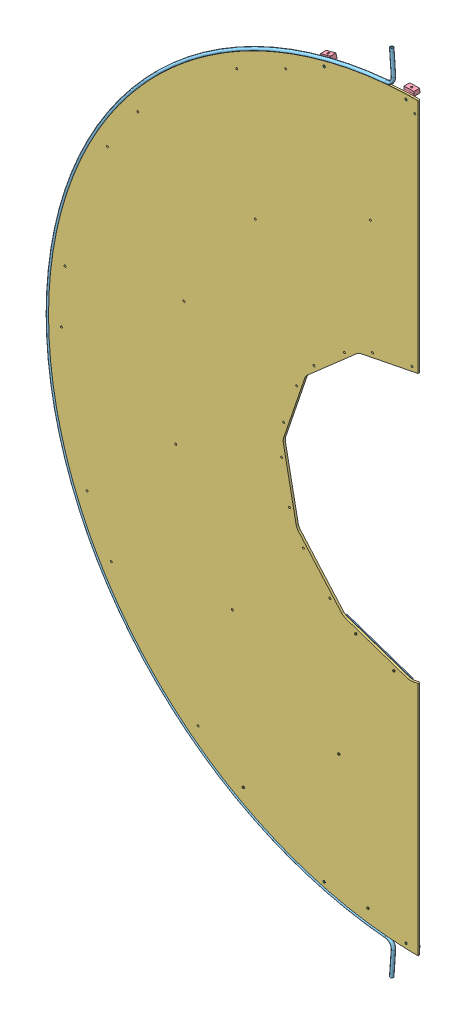
SolidWorks assembly FVTX read_ckt_brd2_array, configuration No array. Lengths in mm.
Overall size (623.69 1199.01 14.3).
281 component instances, 8 part files, 20 mates.
Components (placement in the parent):
- FVTX rear_ckt_board_assy3-1: FVTX rear_ckt_board_assy3 [outline drawing] x (0.94693 -0.321439 0) z (0 0 -1) size (276.95 346.3 2.31)
  - FVTX rear_ckt_board_assy3-1: FVTX rear_ckt_board_assy3 [outline drawing] at origin size (276.95 346.3 1.59)
  - hirose df18c series receptacle-4: hirose df18c series receptacle [DF18C-60DS-0.4V] at (-42.4321 213.3208 1.5875) x (0.19509 -0.980785 0) z (0 0 1) size (5 14.6 0.73)
  - hirose df18c series receptacle-68: hirose df18c series receptacle [DF18C-60DS-0.4V] at (-44.383 223.1287 1.5875) x (0.19509 -0.980785 0) z (0 0 1) size (5 14.6 0.73)
  - hirose df18c series receptacle-12: hirose df18c series receptacle [DF18C-100DS-0.4V] at (-47.3094 237.8404 1.5875) x (0.19509 -0.980785 0) z (0 0 1) size (5 22.6 0.73)
  - hirose df18c series receptacle-41: hirose df18c series receptacle [DF18C-100DS-0.4V] at (-52.1867 262.3601 1.5875) x (0.19509 -0.980785 0) z (0 0 1) size (5 22.6 0.73)
  - hirose df18c series receptacle-45: hirose df18c series receptacle [DF18C-100DS-0.4V] at (-57.0639 286.8797 1.5875) x (0.19509 -0.980785 0) z (0 0 1) size (5 22.6 0.73)
  - hirose df18c series receptacle-65: hirose df18c series receptacle [DF18C-60DS-0.4V] at (-14.2252 217.0343 1.5875) x (0.065403 -0.997859 0) z (0 0 1) size (5 14.6 0.73)
  - hirose df18c series receptacle-66: hirose df18c series receptacle [DF18C-60DS-0.4V] at (14.2252 217.0343 1.5875) x (-0.065403 -0.997859 0) z (0 0 1) size (5 14.6 0.73)
  - hirose df18c series receptacle-67: hirose df18c series receptacle [DF18C-60DS-0.4V] at (42.4321 213.3208 1.5875) x (-0.19509 -0.980785 0) z (0 0 1) size (5 14.6 0.73)
  - hirose df18c series receptacle-38: hirose df18c series receptacle [DF18C-100DS-0.4V] at (-15.8603 241.9808 1.5875) x (0.065403 -0.997859 0) z (0 0 1) size (5 22.6 0.73)
  - hirose df18c series receptacle-39: hirose df18c series receptacle [DF18C-100DS-0.4V] at (15.8603 241.9808 1.5875) x (-0.065403 -0.997859 0) z (0 0 1) size (5 22.6 0.73)
  - hirose df18c series receptacle-40: hirose df18c series receptacle [DF18C-100DS-0.4V] at (47.3094 237.8404 1.5875) x (-0.19509 -0.980785 0) z (0 0 1) size (5 22.6 0.73)
  - hirose df18c series receptacle-42: hirose df18c series receptacle [DF18C-100DS-0.4V] at (-17.4953 266.9273 1.5875) x (0.065403 -0.997859 0) z (0 0 1) size (5 22.6 0.73)
  - hirose df18c series receptacle-43: hirose df18c series receptacle [DF18C-100DS-0.4V] at (17.4953 266.9273 1.5875) x (-0.065403 -0.997859 0) z (0 0 1) size (5 22.6 0.73)
  - hirose df18c series receptacle-44: hirose df18c series receptacle [DF18C-100DS-0.4V] at (52.1867 262.3601 1.5875) x (-0.19509 -0.980785 0) z (0 0 1) size (5 22.6 0.73)
  - hirose df18c series receptacle-46: hirose df18c series receptacle [DF18C-100DS-0.4V] at (-19.1304 291.8737 1.5875) x (0.065403 -0.997859 0) z (0 0 1) size (5 22.6 0.73)
  - hirose df18c series receptacle-47: hirose df18c series receptacle [DF18C-100DS-0.4V] at (19.1304 291.8737 1.5875) x (-0.065403 -0.997859 0) z (0 0 1) size (5 22.6 0.73)
  - hirose df18c series receptacle-48: hirose df18c series receptacle [DF18C-100DS-0.4V] at (57.0639 286.8797 1.5875) x (-0.19509 -0.980785 0) z (0 0 1) size (5 22.6 0.73)
  - VTX - pan cross head_ai-1: VTX - pan cross head_ai [CR-PHMS 0.112-40x0.25x0.25-N] at (-98.0409 523.0976 3.6195) x (0 0 -1) z (1 0 0) (suppressed, hidden)
  - VTX - pan cross head_ai-2: VTX - pan cross head_ai [CR-PHMS 0.112-40x0.25x0.25-N] at (98.0409 523.0976 3.6195) x (0 0 -1) z (1 0 0) (suppressed, hidden)
  - VTX - pan cross head_ai-3: VTX - pan cross head_ai [CR-PHMS 0.112-40x0.25x0.25-N] at (0 369.15 3.6195) x (0 0 -1) z (1 0 0) (suppressed, hidden)
  - VTX - pan cross head_ai-4: VTX - pan cross head_ai [CR-PHMS 0.112-40x0.25x0.25-N] at (-30 202.35 3.6195) x (0 0 -1) z (1 0 0) (suppressed, hidden)
  - VTX - pan cross head_ai-5: VTX - pan cross head_ai [CR-PHMS 0.112-40x0.25x0.25-N] at (30 202.35 3.6195) x (0 0 -1) z (1 0 0) (suppressed, hidden)
  - hirose df18c series receptacle-69: hirose df18c series receptacle [DF18C-100DS-0.4V] at (-49.2603 247.6483 1.5875) x (0.19509 -0.980785 0) z (0 0 1) size (5 22.6 0.73)
  - hirose df18c series receptacle-70: hirose df18c series receptacle [DF18C-100DS-0.4V] at (-54.1376 272.1679 1.5875) x (0.19509 -0.980785 0) z (0 0 1) size (5 22.6 0.73)
  - hirose df18c series receptacle-71: hirose df18c series receptacle [DF18C-100DS-0.4V] at (-59.0148 296.6875 1.5875) x (0.19509 -0.980785 0) z (0 0 1) size (5 22.6 0.73)
  - hirose df18c series receptacle-72: hirose df18c series receptacle [DF18C-60DS-0.4V] at (-14.8792 227.0129 1.5875) x (0.065403 -0.997859 0) z (0 0 1) size (5 14.6 0.73)
  - hirose df18c series receptacle-73: hirose df18c series receptacle [DF18C-60DS-0.4V] at (14.8792 227.0129 1.5875) x (-0.065403 -0.997859 0) z (0 0 1) size (5 14.6 0.73)
  - hirose df18c series receptacle-74: hirose df18c series receptacle [DF18C-60DS-0.4V] at (44.383 223.1287 1.5875) x (-0.19509 -0.980785 0) z (0 0 1) size (5 14.6 0.73)
  - hirose df18c series receptacle-75: hirose df18c series receptacle [DF18C-100DS-0.4V] at (-16.5143 251.9594 1.5875) x (0.065403 -0.997859 0) z (0 0 1) size (5 22.6 0.73)
  - hirose df18c series receptacle-76: hirose df18c series receptacle [DF18C-100DS-0.4V] at (16.5143 251.9594 1.5875) x (-0.065403 -0.997859 0) z (0 0 1) size (5 22.6 0.73)
  - hirose df18c series receptacle-77: hirose df18c series receptacle [DF18C-100DS-0.4V] at (49.2603 247.6483 1.5875) x (-0.19509 -0.980785 0) z (0 0 1) size (5 22.6 0.73)
  - hirose df18c series receptacle-78: hirose df18c series receptacle [DF18C-100DS-0.4V] at (-18.1494 276.9059 1.5875) x (0.065403 -0.997859 0) z (0 0 1) size (5 22.6 0.73)
  - hirose df18c series receptacle-79: hirose df18c series receptacle [DF18C-100DS-0.4V] at (18.1494 276.9059 1.5875) x (-0.065403 -0.997859 0) z (0 0 1) size (5 22.6 0.73)
  - hirose df18c series receptacle-80: hirose df18c series receptacle [DF18C-100DS-0.4V] at (54.1376 272.1679 1.5875) x (-0.19509 -0.980785 0) z (0 0 1) size (5 22.6 0.73)
  - hirose df18c series receptacle-81: hirose df18c series receptacle [DF18C-100DS-0.4V] at (-19.7844 301.8523 1.5875) x (0.065403 -0.997859 0) z (0 0 1) size (5 22.6 0.73)
  - hirose df18c series receptacle-82: hirose df18c series receptacle [DF18C-100DS-0.4V] at (19.7844 301.8523 1.5875) x (-0.065403 -0.997859 0) z (0 0 1) size (5 22.6 0.73)
  - hirose df18c series receptacle-83: hirose df18c series receptacle [DF18C-100DS-0.4V] at (59.0148 296.6875 1.5875) x (-0.19509 -0.980785 0) z (0 0 1) size (5 22.6 0.73)
- Bigwheel plate assy-1: Bigwheel plate assy [FVTX Cooling Plate] at (0 0 2.0875) x (1 0 0) z (0 0 -1) size (554.56 1199.01 14)
  - Bigwheel plate-1: Bigwheel plate [FVTX Cooling Plate] at origin size (550.41 1103.14 3.17)
  - Bigwheel plate mounting block-1: Bigwheel plate mounting block [Default] at (-19.3971 -555.4614 1.5875) x (0 0 -1) z (-0.999391 0.034899 0) size (10.03 15 15)
  - Bigwheel plate mounting block-2: Bigwheel plate mounting block [Default] at (-19.3971 555.4614 1.5875) x (0 0 -1) z (0.999391 0.034899 0) size (10.03 15 15)
  - Bigwheel plate mounting block-3: Bigwheel plate mounting block [Default] at (-143.8516 536.8616 1.5875) x (0 0 -1) z (0.965926 0.258819 0) size (10.03 15 15)
  - Bigwheel plate mounting block-4: Bigwheel plate mounting block [Default] at (-143.8516 -536.8616 1.5875) x (0 0 -1) z (-0.965926 0.258819 0) size (10.03 15 15)
  - Bigwheel plate mounting block-6: Bigwheel plate mounting block [Default] at (-17.6242 -504.6924 -1.5875) x (0 0 1) z (0.999391 -0.034899 0) size (10.03 15 15) (suppressed, hidden)
  - Bigwheel plate mounting block-8: Bigwheel plate mounting block [Default] at (-17.6242 504.6924 -1.5875) x (0 0 1) z (-0.999391 -0.034899 0) size (10.03 15 15) (suppressed, hidden)
  - Bigwheel plate mounting block-10: Bigwheel plate mounting block [Default] at (-130.7036 487.7925 -1.5875) x (0 0 1) z (-0.965926 -0.258819 0) size (10.03 15 15) (suppressed, hidden)
  - Bigwheel plate mounting block-12: Bigwheel plate mounting block [Default] at (-130.7036 -487.7925 -1.5875) x (0 0 1) z (0.965926 -0.258819 0) size (10.03 15 15) (suppressed, hidden)
  - Bigwheel plate cooling tube-1: Bigwheel plate cooling tube [FVTX Bigwheel] x (0 1 0) z (0 0 1) size (1199.01 518.62 4.76)
  - Bigwheels seal-1: Bigwheels seal [Default] at (0 0 -20.437) (suppressed, hidden)
  - VTX - Flat Head Screw_AM-1: VTX - Flat Head Screw_AM [B18.6.7M - M3 x 0.5 x 5 Type I Cross Recessed FHMS --5N] at (-18.9969 543.9997 3.225) x (0 0 -1) z (-0.92007 -0.391753 0) size (5 5.5 5.5)
  - VTX - Flat Head Screw_AM-2: VTX - Flat Head Screw_AM [B18.6.7M - M3 x 0.5 x 5 Type I Cross Recessed FHMS --5N] at (-140.8833 525.7836 3.225) x (0 0 -1) z (-0.029274 -0.999571 0) size (5 5.5 5.5)
  - VTX - Flat Head Screw_AM-3: VTX - Flat Head Screw_AM [B18.6.7M - M3 x 0.5 x 5 Type I Cross Recessed FHMS --5N] at (-18.9969 -543.9997 3.225) x (0 0 -1) z (-0.924921 -0.38016 0) size (5 5.5 5.5)
  - VTX - Flat Head Screw_AM-4: VTX - Flat Head Screw_AM [B18.6.7M - M3 x 0.5 x 5 Type I Cross Recessed FHMS --5N] at (-140.8833 -525.7836 3.225) x (0 0 -1) z (0.994263 0.106964 0) size (5 5.5 5.5)
- Bigwheels seal-1: Bigwheels seal [FVTX seal] at (0 0 -21.2044) (suppressed, hidden)
- VTX - pan cross head_ai-1: VTX - pan cross head_ai [CR-PHMS 0.112-40x0.25x0.25-N] at (-118.6594 -349.5593 -3.6195) x (0 0 1) z (-1 0 0)
- VTX - pan cross head_ai-2: VTX - pan cross head_ai [CR-PHMS 0.112-40x0.25x0.25-N] at (-75.3063 -526.8511 -3.6195) x (0 0 1) z (-1 0 0)
- VTX - pan cross head_ai-4: VTX - pan cross head_ai [CR-PHMS 0.112-40x0.25x0.25-N] at (-260.9821 -463.8226 -3.6195) x (0 0 1) z (-1 0 0)
- VTX - pan cross head_ai-5: VTX - pan cross head_ai [CR-PHMS 0.112-40x0.25x0.25-N] at (-93.4512 -181.9681 -3.6195) x (0 0 1) z (-1 0 0)
- VTX - pan cross head_ai-6: VTX - pan cross head_ai [CR-PHMS 0.112-40x0.25x0.25-N] at (-36.6354 -201.2545 -3.6195) x (0 0 1) z (-1 0 0)
- VTX - pan cross head_ai-7: VTX - pan cross head_ai [CR-PHMS 0.112-40x0.25x0.25-N] at (-132.3544 -155.9738 -3.6195) x (0 0 1) z (-0.866025 0.5 0) (suppressed, hidden)
- VTX - pan cross head_ai-8: VTX - pan cross head_ai [CR-PHMS 0.112-40x0.25x0.25-N] at (-192.6092 -68.9001 -3.6195) x (0 0 1) z (-0.5 0.866025 0) (suppressed, hidden)
- VTX - pan cross head_ai-9: VTX - pan cross head_ai [CR-PHMS 0.112-40x0.25x0.25-N] at (-201.2545 36.6354 -3.6195) x (0 0 1) z (0 1 0) (suppressed, hidden)
- VTX - pan cross head_ai-10: VTX - pan cross head_ai [CR-PHMS 0.112-40x0.25x0.25-N] at (-155.9738 132.3544 -3.6195) x (0 0 1) z (0.5 0.866025 0) (suppressed, hidden)
- VTX - pan cross head_ai-11: VTX - pan cross head_ai [CR-PHMS 0.112-40x0.25x0.25-N] at (-68.9001 192.6092 -3.6195) x (0 0 1) z (0.866025 0.5 0) (suppressed, hidden)
- VTX - pan cross head_ai-12: VTX - pan cross head_ai [CR-PHMS 0.112-40x0.25x0.25-N] at (-171.9152 -110.8634 -3.6195) x (0 0 1) z (-0.866025 0.5 0) (suppressed, hidden)
- VTX - pan cross head_ai-13: VTX - pan cross head_ai [CR-PHMS 0.112-40x0.25x0.25-N] at (-204.3146 -10.053 -3.6195) x (0 0 1) z (-0.5 0.866025 0) (suppressed, hidden)
- VTX - pan cross head_ai-14: VTX - pan cross head_ai [CR-PHMS 0.112-40x0.25x0.25-N] at (-181.9681 93.4512 -3.6195) x (0 0 1) z (0 1 0) (suppressed, hidden)
- VTX - pan cross head_ai-15: VTX - pan cross head_ai [CR-PHMS 0.112-40x0.25x0.25-N] at (-110.8634 171.9152 -3.6195) x (0 0 1) z (0.5 0.866025 0) (suppressed, hidden)
- VTX - pan cross head_ai-16: VTX - pan cross head_ai [CR-PHMS 0.112-40x0.25x0.25-N] at (-10.053 204.3146 -3.6195) x (0 0 1) z (0.866025 0.5 0) (suppressed, hidden)
- VTX - pan cross head_ai-17: VTX - pan cross head_ai [CR-PHMS 0.112-40x0.25x0.25-N] at (-457.9285 -271.1911 -3.6195) x (0 0 1) z (-0.866025 0.5 0) (suppressed, hidden)
- VTX - pan cross head_ai-18: VTX - pan cross head_ai [CR-PHMS 0.112-40x0.25x0.25-N] at (-532.1732 -5.8942 -3.6195) x (0 0 1) z (-0.5 0.866025 0) (suppressed, hidden)
- VTX - pan cross head_ai-19: VTX - pan cross head_ai [CR-PHMS 0.112-40x0.25x0.25-N] at (-463.8226 260.9821 -3.6195) x (0 0 1) z (0 1 0) (suppressed, hidden)
- VTX - pan cross head_ai-20: VTX - pan cross head_ai [CR-PHMS 0.112-40x0.25x0.25-N] at (-271.1911 457.9285 -3.6195) x (0 0 1) z (0.5 0.866025 0) (suppressed, hidden)
- VTX - pan cross head_ai-21: VTX - pan cross head_ai [CR-PHMS 0.112-40x0.25x0.25-N] at (-5.8942 532.1732 -3.6195) x (0 0 1) z (0.866025 0.5 0) (suppressed, hidden)
- VTX - pan cross head_ai-22: VTX - pan cross head_ai [CR-PHMS 0.112-40x0.25x0.25-N] at (-328.6427 -418.6133 -3.6195) x (0 0 1) z (-0.866025 0.5 0) (suppressed, hidden)
- VTX - pan cross head_ai-23: VTX - pan cross head_ai [CR-PHMS 0.112-40x0.25x0.25-N] at (-493.9196 -198.2084 -3.6195) x (0 0 1) z (-0.5 0.866025 0) (suppressed, hidden)
- VTX - pan cross head_ai-24: VTX - pan cross head_ai [CR-PHMS 0.112-40x0.25x0.25-N] at (-526.8511 75.3063 -3.6195) x (0 0 1) z (0 1 0) (suppressed, hidden)
- VTX - pan cross head_ai-25: VTX - pan cross head_ai [CR-PHMS 0.112-40x0.25x0.25-N] at (-418.6133 328.6427 -3.6195) x (0 0 1) z (0.5 0.866025 0) (suppressed, hidden)
- VTX - pan cross head_ai-26: VTX - pan cross head_ai [CR-PHMS 0.112-40x0.25x0.25-N] at (-198.2084 493.9196 -3.6195) x (0 0 1) z (0.866025 0.5 0) (suppressed, hidden)
- VTX - pan cross head_ai-27: VTX - pan cross head_ai [CR-PHMS 0.112-40x0.25x0.25-N] at (-277.5417 -243.3975 -3.6195) x (0 0 1) z (-0.866025 0.5 0) (suppressed, hidden)
- VTX - pan cross head_ai-28: VTX - pan cross head_ai [CR-PHMS 0.112-40x0.25x0.25-N] at (-362.0569 -72.0176 -3.6195) x (0 0 1) z (-0.5 0.866025 0) (suppressed, hidden)
- VTX - pan cross head_ai-29: VTX - pan cross head_ai [CR-PHMS 0.112-40x0.25x0.25-N] at (-349.5593 118.6594 -3.6195) x (0 0 1) z (0 1 0) (suppressed, hidden)
- VTX - pan cross head_ai-30: VTX - pan cross head_ai [CR-PHMS 0.112-40x0.25x0.25-N] at (-243.3975 277.5417 -3.6195) x (0 0 1) z (0.5 0.866025 0) (suppressed, hidden)
- VTX - pan cross head_ai-31: VTX - pan cross head_ai [CR-PHMS 0.112-40x0.25x0.25-N] at (-72.0176 362.0569 -3.6195) x (0 0 1) z (0.866025 0.5 0) (suppressed, hidden)
- FVTX rear_ckt_board_assy3-16: FVTX rear_ckt_board_assy3 [outline drawing] x (0.659346 -0.75184 0) z (0 0 -1) size (276.95 346.3 2.31) (suppressed, hidden)
  - FVTX rear_ckt_board_assy3-1: FVTX rear_ckt_board_assy3 [outline drawing] at origin size (276.95 346.3 1.59)
  - hirose df18c series receptacle-4: hirose df18c series receptacle [DF18C-60DS-0.4V] at (-42.4321 213.3208 1.5875) x (0.19509 -0.980785 0) z (0 0 1) size (5 14.6 0.73)
  - hirose df18c series receptacle-68: hirose df18c series receptacle [DF18C-60DS-0.4V] at (-44.383 223.1287 1.5875) x (0.19509 -0.980785 0) z (0 0 1) size (5 14.6 0.73)
  - hirose df18c series receptacle-12: hirose df18c series receptacle [DF18C-100DS-0.4V] at (-47.3094 237.8404 1.5875) x (0.19509 -0.980785 0) z (0 0 1) size (5 22.6 0.73)
  - hirose df18c series receptacle-41: hirose df18c series receptacle [DF18C-100DS-0.4V] at (-52.1867 262.3601 1.5875) x (0.19509 -0.980785 0) z (0 0 1) size (5 22.6 0.73)
  - hirose df18c series receptacle-45: hirose df18c series receptacle [DF18C-100DS-0.4V] at (-57.0639 286.8797 1.5875) x (0.19509 -0.980785 0) z (0 0 1) size (5 22.6 0.73)
  - hirose df18c series receptacle-65: hirose df18c series receptacle [DF18C-60DS-0.4V] at (-14.2252 217.0343 1.5875) x (0.065403 -0.997859 0) z (0 0 1) size (5 14.6 0.73)
  - hirose df18c series receptacle-66: hirose df18c series receptacle [DF18C-60DS-0.4V] at (14.2252 217.0343 1.5875) x (-0.065403 -0.997859 0) z (0 0 1) size (5 14.6 0.73)
  - hirose df18c series receptacle-67: hirose df18c series receptacle [DF18C-60DS-0.4V] at (42.4321 213.3208 1.5875) x (-0.19509 -0.980785 0) z (0 0 1) size (5 14.6 0.73)
  - hirose df18c series receptacle-38: hirose df18c series receptacle [DF18C-100DS-0.4V] at (-15.8603 241.9808 1.5875) x (0.065403 -0.997859 0) z (0 0 1) size (5 22.6 0.73)
  - hirose df18c series receptacle-39: hirose df18c series receptacle [DF18C-100DS-0.4V] at (15.8603 241.9808 1.5875) x (-0.065403 -0.997859 0) z (0 0 1) size (5 22.6 0.73)
  - hirose df18c series receptacle-40: hirose df18c series receptacle [DF18C-100DS-0.4V] at (47.3094 237.8404 1.5875) x (-0.19509 -0.980785 0) z (0 0 1) size (5 22.6 0.73)
  - hirose df18c series receptacle-42: hirose df18c series receptacle [DF18C-100DS-0.4V] at (-17.4953 266.9273 1.5875) x (0.065403 -0.997859 0) z (0 0 1) size (5 22.6 0.73)
  - hirose df18c series receptacle-43: hirose df18c series receptacle [DF18C-100DS-0.4V] at (17.4953 266.9273 1.5875) x (-0.065403 -0.997859 0) z (0 0 1) size (5 22.6 0.73)
  - hirose df18c series receptacle-44: hirose df18c series receptacle [DF18C-100DS-0.4V] at (52.1867 262.3601 1.5875) x (-0.19509 -0.980785 0) z (0 0 1) size (5 22.6 0.73)
  - hirose df18c series receptacle-46: hirose df18c series receptacle [DF18C-100DS-0.4V] at (-19.1304 291.8737 1.5875) x (0.065403 -0.997859 0) z (0 0 1) size (5 22.6 0.73)
  - hirose df18c series receptacle-47: hirose df18c series receptacle [DF18C-100DS-0.4V] at (19.1304 291.8737 1.5875) x (-0.065403 -0.997859 0) z (0 0 1) size (5 22.6 0.73)
  - hirose df18c series receptacle-48: hirose df18c series receptacle [DF18C-100DS-0.4V] at (57.0639 286.8797 1.5875) x (-0.19509 -0.980785 0) z (0 0 1) size (5 22.6 0.73)
  - VTX - pan cross head_ai-1: VTX - pan cross head_ai [CR-PHMS 0.112-40x0.25x0.25-N] at (-98.0409 523.0976 3.6195) x (0 0 -1) z (1 0 0) (suppressed, hidden)
  - VTX - pan cross head_ai-2: VTX - pan cross head_ai [CR-PHMS 0.112-40x0.25x0.25-N] at (98.0409 523.0976 3.6195) x (0 0 -1) z (1 0 0) (suppressed, hidden)
  - VTX - pan cross head_ai-3: VTX - pan cross head_ai [CR-PHMS 0.112-40x0.25x0.25-N] at (0 369.15 3.6195) x (0 0 -1) z (1 0 0) (suppressed, hidden)
  - VTX - pan cross head_ai-4: VTX - pan cross head_ai [CR-PHMS 0.112-40x0.25x0.25-N] at (-30 202.35 3.6195) x (0 0 -1) z (1 0 0) (suppressed, hidden)
  - VTX - pan cross head_ai-5: VTX - pan cross head_ai [CR-PHMS 0.112-40x0.25x0.25-N] at (30 202.35 3.6195) x (0 0 -1) z (1 0 0) (suppressed, hidden)
  - hirose df18c series receptacle-69: hirose df18c series receptacle [DF18C-100DS-0.4V] at (-49.2603 247.6483 1.5875) x (0.19509 -0.980785 0) z (0 0 1) size (5 22.6 0.73)
  - hirose df18c series receptacle-70: hirose df18c series receptacle [DF18C-100DS-0.4V] at (-54.1376 272.1679 1.5875) x (0.19509 -0.980785 0) z (0 0 1) size (5 22.6 0.73)
  - hirose df18c series receptacle-71: hirose df18c series receptacle [DF18C-100DS-0.4V] at (-59.0148 296.6875 1.5875) x (0.19509 -0.980785 0) z (0 0 1) size (5 22.6 0.73)
  - hirose df18c series receptacle-72: hirose df18c series receptacle [DF18C-60DS-0.4V] at (-14.8792 227.0129 1.5875) x (0.065403 -0.997859 0) z (0 0 1) size (5 14.6 0.73)
  - hirose df18c series receptacle-73: hirose df18c series receptacle [DF18C-60DS-0.4V] at (14.8792 227.0129 1.5875) x (-0.065403 -0.997859 0) z (0 0 1) size (5 14.6 0.73)
  - hirose df18c series receptacle-74: hirose df18c series receptacle [DF18C-60DS-0.4V] at (44.383 223.1287 1.5875) x (-0.19509 -0.980785 0) z (0 0 1) size (5 14.6 0.73)
  - hirose df18c series receptacle-75: hirose df18c series receptacle [DF18C-100DS-0.4V] at (-16.5143 251.9594 1.5875) x (0.065403 -0.997859 0) z (0 0 1) size (5 22.6 0.73)
  - hirose df18c series receptacle-76: hirose df18c series receptacle [DF18C-100DS-0.4V] at (16.5143 251.9594 1.5875) x (-0.065403 -0.997859 0) z (0 0 1) size (5 22.6 0.73)
  - hirose df18c series receptacle-77: hirose df18c series receptacle [DF18C-100DS-0.4V] at (49.2603 247.6483 1.5875) x (-0.19509 -0.980785 0) z (0 0 1) size (5 22.6 0.73)
  - hirose df18c series receptacle-78: hirose df18c series receptacle [DF18C-100DS-0.4V] at (-18.1494 276.9059 1.5875) x (0.065403 -0.997859 0) z (0 0 1) size (5 22.6 0.73)
  - hirose df18c series receptacle-79: hirose df18c series receptacle [DF18C-100DS-0.4V] at (18.1494 276.9059 1.5875) x (-0.065403 -0.997859 0) z (0 0 1) size (5 22.6 0.73)
  - hirose df18c series receptacle-80: hirose df18c series receptacle [DF18C-100DS-0.4V] at (54.1376 272.1679 1.5875) x (-0.19509 -0.980785 0) z (0 0 1) size (5 22.6 0.73)
  - hirose df18c series receptacle-81: hirose df18c series receptacle [DF18C-100DS-0.4V] at (-19.7844 301.8523 1.5875) x (0.065403 -0.997859 0) z (0 0 1) size (5 22.6 0.73)
  - hirose df18c series receptacle-82: hirose df18c series receptacle [DF18C-100DS-0.4V] at (19.7844 301.8523 1.5875) x (-0.065403 -0.997859 0) z (0 0 1) size (5 22.6 0.73)
  - hirose df18c series receptacle-83: hirose df18c series receptacle [DF18C-100DS-0.4V] at (59.0148 296.6875 1.5875) x (-0.19509 -0.980785 0) z (0 0 1) size (5 22.6 0.73)
- FVTX rear_ckt_board_assy3-17: FVTX rear_ckt_board_assy3 [outline drawing] x (0.19509 -0.980785 0) z (0 0 -1) size (276.95 346.3 2.31) (suppressed, hidden)
  - FVTX rear_ckt_board_assy3-1: FVTX rear_ckt_board_assy3 [outline drawing] at origin size (276.95 346.3 1.59)
  - hirose df18c series receptacle-4: hirose df18c series receptacle [DF18C-60DS-0.4V] at (-42.4321 213.3208 1.5875) x (0.19509 -0.980785 0) z (0 0 1) size (5 14.6 0.73)
  - hirose df18c series receptacle-68: hirose df18c series receptacle [DF18C-60DS-0.4V] at (-44.383 223.1287 1.5875) x (0.19509 -0.980785 0) z (0 0 1) size (5 14.6 0.73)
  - hirose df18c series receptacle-12: hirose df18c series receptacle [DF18C-100DS-0.4V] at (-47.3094 237.8404 1.5875) x (0.19509 -0.980785 0) z (0 0 1) size (5 22.6 0.73)
  - hirose df18c series receptacle-41: hirose df18c series receptacle [DF18C-100DS-0.4V] at (-52.1867 262.3601 1.5875) x (0.19509 -0.980785 0) z (0 0 1) size (5 22.6 0.73)
  - hirose df18c series receptacle-45: hirose df18c series receptacle [DF18C-100DS-0.4V] at (-57.0639 286.8797 1.5875) x (0.19509 -0.980785 0) z (0 0 1) size (5 22.6 0.73)
  - hirose df18c series receptacle-65: hirose df18c series receptacle [DF18C-60DS-0.4V] at (-14.2252 217.0343 1.5875) x (0.065403 -0.997859 0) z (0 0 1) size (5 14.6 0.73)
  - hirose df18c series receptacle-66: hirose df18c series receptacle [DF18C-60DS-0.4V] at (14.2252 217.0343 1.5875) x (-0.065403 -0.997859 0) z (0 0 1) size (5 14.6 0.73)
  - hirose df18c series receptacle-67: hirose df18c series receptacle [DF18C-60DS-0.4V] at (42.4321 213.3208 1.5875) x (-0.19509 -0.980785 0) z (0 0 1) size (5 14.6 0.73)
  - hirose df18c series receptacle-38: hirose df18c series receptacle [DF18C-100DS-0.4V] at (-15.8603 241.9808 1.5875) x (0.065403 -0.997859 0) z (0 0 1) size (5 22.6 0.73)
  - hirose df18c series receptacle-39: hirose df18c series receptacle [DF18C-100DS-0.4V] at (15.8603 241.9808 1.5875) x (-0.065403 -0.997859 0) z (0 0 1) size (5 22.6 0.73)
  - hirose df18c series receptacle-40: hirose df18c series receptacle [DF18C-100DS-0.4V] at (47.3094 237.8404 1.5875) x (-0.19509 -0.980785 0) z (0 0 1) size (5 22.6 0.73)
  - hirose df18c series receptacle-42: hirose df18c series receptacle [DF18C-100DS-0.4V] at (-17.4953 266.9273 1.5875) x (0.065403 -0.997859 0) z (0 0 1) size (5 22.6 0.73)
  - hirose df18c series receptacle-43: hirose df18c series receptacle [DF18C-100DS-0.4V] at (17.4953 266.9273 1.5875) x (-0.065403 -0.997859 0) z (0 0 1) size (5 22.6 0.73)
  - hirose df18c series receptacle-44: hirose df18c series receptacle [DF18C-100DS-0.4V] at (52.1867 262.3601 1.5875) x (-0.19509 -0.980785 0) z (0 0 1) size (5 22.6 0.73)
  - hirose df18c series receptacle-46: hirose df18c series receptacle [DF18C-100DS-0.4V] at (-19.1304 291.8737 1.5875) x (0.065403 -0.997859 0) z (0 0 1) size (5 22.6 0.73)
  - hirose df18c series receptacle-47: hirose df18c series receptacle [DF18C-100DS-0.4V] at (19.1304 291.8737 1.5875) x (-0.065403 -0.997859 0) z (0 0 1) size (5 22.6 0.73)
  - hirose df18c series receptacle-48: hirose df18c series receptacle [DF18C-100DS-0.4V] at (57.0639 286.8797 1.5875) x (-0.19509 -0.980785 0) z (0 0 1) size (5 22.6 0.73)
  - VTX - pan cross head_ai-1: VTX - pan cross head_ai [CR-PHMS 0.112-40x0.25x0.25-N] at (-98.0409 523.0976 3.6195) x (0 0 -1) z (1 0 0) (suppressed, hidden)
  - VTX - pan cross head_ai-2: VTX - pan cross head_ai [CR-PHMS 0.112-40x0.25x0.25-N] at (98.0409 523.0976 3.6195) x (0 0 -1) z (1 0 0) (suppressed, hidden)
  - VTX - pan cross head_ai-3: VTX - pan cross head_ai [CR-PHMS 0.112-40x0.25x0.25-N] at (0 369.15 3.6195) x (0 0 -1) z (1 0 0) (suppressed, hidden)
  - VTX - pan cross head_ai-4: VTX - pan cross head_ai [CR-PHMS 0.112-40x0.25x0.25-N] at (-30 202.35 3.6195) x (0 0 -1) z (1 0 0) (suppressed, hidden)
  - VTX - pan cross head_ai-5: VTX - pan cross head_ai [CR-PHMS 0.112-40x0.25x0.25-N] at (30 202.35 3.6195) x (0 0 -1) z (1 0 0) (suppressed, hidden)
  - hirose df18c series receptacle-69: hirose df18c series receptacle [DF18C-100DS-0.4V] at (-49.2603 247.6483 1.5875) x (0.19509 -0.980785 0) z (0 0 1) size (5 22.6 0.73)
  - hirose df18c series receptacle-70: hirose df18c series receptacle [DF18C-100DS-0.4V] at (-54.1376 272.1679 1.5875) x (0.19509 -0.980785 0) z (0 0 1) size (5 22.6 0.73)
  - hirose df18c series receptacle-71: hirose df18c series receptacle [DF18C-100DS-0.4V] at (-59.0148 296.6875 1.5875) x (0.19509 -0.980785 0) z (0 0 1) size (5 22.6 0.73)
  - hirose df18c series receptacle-72: hirose df18c series receptacle [DF18C-60DS-0.4V] at (-14.8792 227.0129 1.5875) x (0.065403 -0.997859 0) z (0 0 1) size (5 14.6 0.73)
  - hirose df18c series receptacle-73: hirose df18c series receptacle [DF18C-60DS-0.4V] at (14.8792 227.0129 1.5875) x (-0.065403 -0.997859 0) z (0 0 1) size (5 14.6 0.73)
  - hirose df18c series receptacle-74: hirose df18c series receptacle [DF18C-60DS-0.4V] at (44.383 223.1287 1.5875) x (-0.19509 -0.980785 0) z (0 0 1) size (5 14.6 0.73)
  - hirose df18c series receptacle-75: hirose df18c series receptacle [DF18C-100DS-0.4V] at (-16.5143 251.9594 1.5875) x (0.065403 -0.997859 0) z (0 0 1) size (5 22.6 0.73)
  - hirose df18c series receptacle-76: hirose df18c series receptacle [DF18C-100DS-0.4V] at (16.5143 251.9594 1.5875) x (-0.065403 -0.997859 0) z (0 0 1) size (5 22.6 0.73)
  - hirose df18c series receptacle-77: hirose df18c series receptacle [DF18C-100DS-0.4V] at (49.2603 247.6483 1.5875) x (-0.19509 -0.980785 0) z (0 0 1) size (5 22.6 0.73)
  - hirose df18c series receptacle-78: hirose df18c series receptacle [DF18C-100DS-0.4V] at (-18.1494 276.9059 1.5875) x (0.065403 -0.997859 0) z (0 0 1) size (5 22.6 0.73)
  - hirose df18c series receptacle-79: hirose df18c series receptacle [DF18C-100DS-0.4V] at (18.1494 276.9059 1.5875) x (-0.065403 -0.997859 0) z (0 0 1) size (5 22.6 0.73)
  - hirose df18c series receptacle-80: hirose df18c series receptacle [DF18C-100DS-0.4V] at (54.1376 272.1679 1.5875) x (-0.19509 -0.980785 0) z (0 0 1) size (5 22.6 0.73)
  - hirose df18c series receptacle-81: hirose df18c series receptacle [DF18C-100DS-0.4V] at (-19.7844 301.8523 1.5875) x (0.065403 -0.997859 0) z (0 0 1) size (5 22.6 0.73)
  - hirose df18c series receptacle-82: hirose df18c series receptacle [DF18C-100DS-0.4V] at (19.7844 301.8523 1.5875) x (-0.065403 -0.997859 0) z (0 0 1) size (5 22.6 0.73)
  - hirose df18c series receptacle-83: hirose df18c series receptacle [DF18C-100DS-0.4V] at (59.0148 296.6875 1.5875) x (-0.19509 -0.980785 0) z (0 0 1) size (5 22.6 0.73)
- FVTX rear_ckt_board_assy3-18: FVTX rear_ckt_board_assy3 [outline drawing] x (-0.321439 -0.94693 0) z (0 0 -1) size (276.95 346.3 2.31) (suppressed, hidden)
  - FVTX rear_ckt_board_assy3-1: FVTX rear_ckt_board_assy3 [outline drawing] at origin size (276.95 346.3 1.59)
  - hirose df18c series receptacle-4: hirose df18c series receptacle [DF18C-60DS-0.4V] at (-42.4321 213.3208 1.5875) x (0.19509 -0.980785 0) z (0 0 1) size (5 14.6 0.73)
  - hirose df18c series receptacle-68: hirose df18c series receptacle [DF18C-60DS-0.4V] at (-44.383 223.1287 1.5875) x (0.19509 -0.980785 0) z (0 0 1) size (5 14.6 0.73)
  - hirose df18c series receptacle-12: hirose df18c series receptacle [DF18C-100DS-0.4V] at (-47.3094 237.8404 1.5875) x (0.19509 -0.980785 0) z (0 0 1) size (5 22.6 0.73)
  - hirose df18c series receptacle-41: hirose df18c series receptacle [DF18C-100DS-0.4V] at (-52.1867 262.3601 1.5875) x (0.19509 -0.980785 0) z (0 0 1) size (5 22.6 0.73)
  - hirose df18c series receptacle-45: hirose df18c series receptacle [DF18C-100DS-0.4V] at (-57.0639 286.8797 1.5875) x (0.19509 -0.980785 0) z (0 0 1) size (5 22.6 0.73)
  - hirose df18c series receptacle-65: hirose df18c series receptacle [DF18C-60DS-0.4V] at (-14.2252 217.0343 1.5875) x (0.065403 -0.997859 0) z (0 0 1) size (5 14.6 0.73)
  - hirose df18c series receptacle-66: hirose df18c series receptacle [DF18C-60DS-0.4V] at (14.2252 217.0343 1.5875) x (-0.065403 -0.997859 0) z (0 0 1) size (5 14.6 0.73)
  - hirose df18c series receptacle-67: hirose df18c series receptacle [DF18C-60DS-0.4V] at (42.4321 213.3208 1.5875) x (-0.19509 -0.980785 0) z (0 0 1) size (5 14.6 0.73)
  - hirose df18c series receptacle-38: hirose df18c series receptacle [DF18C-100DS-0.4V] at (-15.8603 241.9808 1.5875) x (0.065403 -0.997859 0) z (0 0 1) size (5 22.6 0.73)
  - hirose df18c series receptacle-39: hirose df18c series receptacle [DF18C-100DS-0.4V] at (15.8603 241.9808 1.5875) x (-0.065403 -0.997859 0) z (0 0 1) size (5 22.6 0.73)
  - hirose df18c series receptacle-40: hirose df18c series receptacle [DF18C-100DS-0.4V] at (47.3094 237.8404 1.5875) x (-0.19509 -0.980785 0) z (0 0 1) size (5 22.6 0.73)
  - hirose df18c series receptacle-42: hirose df18c series receptacle [DF18C-100DS-0.4V] at (-17.4953 266.9273 1.5875) x (0.065403 -0.997859 0) z (0 0 1) size (5 22.6 0.73)
  - hirose df18c series receptacle-43: hirose df18c series receptacle [DF18C-100DS-0.4V] at (17.4953 266.9273 1.5875) x (-0.065403 -0.997859 0) z (0 0 1) size (5 22.6 0.73)
  - hirose df18c series receptacle-44: hirose df18c series receptacle [DF18C-100DS-0.4V] at (52.1867 262.3601 1.5875) x (-0.19509 -0.980785 0) z (0 0 1) size (5 22.6 0.73)
  - hirose df18c series receptacle-46: hirose df18c series receptacle [DF18C-100DS-0.4V] at (-19.1304 291.8737 1.5875) x (0.065403 -0.997859 0) z (0 0 1) size (5 22.6 0.73)
  - hirose df18c series receptacle-47: hirose df18c series receptacle [DF18C-100DS-0.4V] at (19.1304 291.8737 1.5875) x (-0.065403 -0.997859 0) z (0 0 1) size (5 22.6 0.73)
  - hirose df18c series receptacle-48: hirose df18c series receptacle [DF18C-100DS-0.4V] at (57.0639 286.8797 1.5875) x (-0.19509 -0.980785 0) z (0 0 1) size (5 22.6 0.73)
  - VTX - pan cross head_ai-1: VTX - pan cross head_ai [CR-PHMS 0.112-40x0.25x0.25-N] at (-98.0409 523.0976 3.6195) x (0 0 -1) z (1 0 0) (suppressed, hidden)
  - VTX - pan cross head_ai-2: VTX - pan cross head_ai [CR-PHMS 0.112-40x0.25x0.25-N] at (98.0409 523.0976 3.6195) x (0 0 -1) z (1 0 0) (suppressed, hidden)
  - VTX - pan cross head_ai-3: VTX - pan cross head_ai [CR-PHMS 0.112-40x0.25x0.25-N] at (0 369.15 3.6195) x (0 0 -1) z (1 0 0) (suppressed, hidden)
  - VTX - pan cross head_ai-4: VTX - pan cross head_ai [CR-PHMS 0.112-40x0.25x0.25-N] at (-30 202.35 3.6195) x (0 0 -1) z (1 0 0) (suppressed, hidden)
  - VTX - pan cross head_ai-5: VTX - pan cross head_ai [CR-PHMS 0.112-40x0.25x0.25-N] at (30 202.35 3.6195) x (0 0 -1) z (1 0 0) (suppressed, hidden)
  - hirose df18c series receptacle-69: hirose df18c series receptacle [DF18C-100DS-0.4V] at (-49.2603 247.6483 1.5875) x (0.19509 -0.980785 0) z (0 0 1) size (5 22.6 0.73)
  - hirose df18c series receptacle-70: hirose df18c series receptacle [DF18C-100DS-0.4V] at (-54.1376 272.1679 1.5875) x (0.19509 -0.980785 0) z (0 0 1) size (5 22.6 0.73)
  - hirose df18c series receptacle-71: hirose df18c series receptacle [DF18C-100DS-0.4V] at (-59.0148 296.6875 1.5875) x (0.19509 -0.980785 0) z (0 0 1) size (5 22.6 0.73)
  - hirose df18c series receptacle-72: hirose df18c series receptacle [DF18C-60DS-0.4V] at (-14.8792 227.0129 1.5875) x (0.065403 -0.997859 0) z (0 0 1) size (5 14.6 0.73)
  - hirose df18c series receptacle-73: hirose df18c series receptacle [DF18C-60DS-0.4V] at (14.8792 227.0129 1.5875) x (-0.065403 -0.997859 0) z (0 0 1) size (5 14.6 0.73)
  - hirose df18c series receptacle-74: hirose df18c series receptacle [DF18C-60DS-0.4V] at (44.383 223.1287 1.5875) x (-0.19509 -0.980785 0) z (0 0 1) size (5 14.6 0.73)
  - hirose df18c series receptacle-75: hirose df18c series receptacle [DF18C-100DS-0.4V] at (-16.5143 251.9594 1.5875) x (0.065403 -0.997859 0) z (0 0 1) size (5 22.6 0.73)
  - hirose df18c series receptacle-76: hirose df18c series receptacle [DF18C-100DS-0.4V] at (16.5143 251.9594 1.5875) x (-0.065403 -0.997859 0) z (0 0 1) size (5 22.6 0.73)
  - hirose df18c series receptacle-77: hirose df18c series receptacle [DF18C-100DS-0.4V] at (49.2603 247.6483 1.5875) x (-0.19509 -0.980785 0) z (0 0 1) size (5 22.6 0.73)
  - hirose df18c series receptacle-78: hirose df18c series receptacle [DF18C-100DS-0.4V] at (-18.1494 276.9059 1.5875) x (0.065403 -0.997859 0) z (0 0 1) size (5 22.6 0.73)
  - hirose df18c series receptacle-79: hirose df18c series receptacle [DF18C-100DS-0.4V] at (18.1494 276.9059 1.5875) x (-0.065403 -0.997859 0) z (0 0 1) size (5 22.6 0.73)
  - hirose df18c series receptacle-80: hirose df18c series receptacle [DF18C-100DS-0.4V] at (54.1376 272.1679 1.5875) x (-0.19509 -0.980785 0) z (0 0 1) size (5 22.6 0.73)
  - hirose df18c series receptacle-81: hirose df18c series receptacle [DF18C-100DS-0.4V] at (-19.7844 301.8523 1.5875) x (0.065403 -0.997859 0) z (0 0 1) size (5 22.6 0.73)
  - hirose df18c series receptacle-82: hirose df18c series receptacle [DF18C-100DS-0.4V] at (19.7844 301.8523 1.5875) x (-0.065403 -0.997859 0) z (0 0 1) size (5 22.6 0.73)
  - hirose df18c series receptacle-83: hirose df18c series receptacle [DF18C-100DS-0.4V] at (59.0148 296.6875 1.5875) x (-0.19509 -0.980785 0) z (0 0 1) size (5 22.6 0.73)
- FVTX rear_ckt_board_assy3-19: FVTX rear_ckt_board_assy3 [outline drawing] x (-0.75184 -0.659346 0) z (0 0 -1) size (276.95 346.3 2.31) (suppressed, hidden)
  - FVTX rear_ckt_board_assy3-1: FVTX rear_ckt_board_assy3 [outline drawing] at origin size (276.95 346.3 1.59)
  - hirose df18c series receptacle-4: hirose df18c series receptacle [DF18C-60DS-0.4V] at (-42.4321 213.3208 1.5875) x (0.19509 -0.980785 0) z (0 0 1) size (5 14.6 0.73)
  - hirose df18c series receptacle-68: hirose df18c series receptacle [DF18C-60DS-0.4V] at (-44.383 223.1287 1.5875) x (0.19509 -0.980785 0) z (0 0 1) size (5 14.6 0.73)
  - hirose df18c series receptacle-12: hirose df18c series receptacle [DF18C-100DS-0.4V] at (-47.3094 237.8404 1.5875) x (0.19509 -0.980785 0) z (0 0 1) size (5 22.6 0.73)
  - hirose df18c series receptacle-41: hirose df18c series receptacle [DF18C-100DS-0.4V] at (-52.1867 262.3601 1.5875) x (0.19509 -0.980785 0) z (0 0 1) size (5 22.6 0.73)
  - hirose df18c series receptacle-45: hirose df18c series receptacle [DF18C-100DS-0.4V] at (-57.0639 286.8797 1.5875) x (0.19509 -0.980785 0) z (0 0 1) size (5 22.6 0.73)
  - hirose df18c series receptacle-65: hirose df18c series receptacle [DF18C-60DS-0.4V] at (-14.2252 217.0343 1.5875) x (0.065403 -0.997859 0) z (0 0 1) size (5 14.6 0.73)
  - hirose df18c series receptacle-66: hirose df18c series receptacle [DF18C-60DS-0.4V] at (14.2252 217.0343 1.5875) x (-0.065403 -0.997859 0) z (0 0 1) size (5 14.6 0.73)
  - hirose df18c series receptacle-67: hirose df18c series receptacle [DF18C-60DS-0.4V] at (42.4321 213.3208 1.5875) x (-0.19509 -0.980785 0) z (0 0 1) size (5 14.6 0.73)
  - hirose df18c series receptacle-38: hirose df18c series receptacle [DF18C-100DS-0.4V] at (-15.8603 241.9808 1.5875) x (0.065403 -0.997859 0) z (0 0 1) size (5 22.6 0.73)
  - hirose df18c series receptacle-39: hirose df18c series receptacle [DF18C-100DS-0.4V] at (15.8603 241.9808 1.5875) x (-0.065403 -0.997859 0) z (0 0 1) size (5 22.6 0.73)
  - hirose df18c series receptacle-40: hirose df18c series receptacle [DF18C-100DS-0.4V] at (47.3094 237.8404 1.5875) x (-0.19509 -0.980785 0) z (0 0 1) size (5 22.6 0.73)
  - hirose df18c series receptacle-42: hirose df18c series receptacle [DF18C-100DS-0.4V] at (-17.4953 266.9273 1.5875) x (0.065403 -0.997859 0) z (0 0 1) size (5 22.6 0.73)
  - hirose df18c series receptacle-43: hirose df18c series receptacle [DF18C-100DS-0.4V] at (17.4953 266.9273 1.5875) x (-0.065403 -0.997859 0) z (0 0 1) size (5 22.6 0.73)
  - hirose df18c series receptacle-44: hirose df18c series receptacle [DF18C-100DS-0.4V] at (52.1867 262.3601 1.5875) x (-0.19509 -0.980785 0) z (0 0 1) size (5 22.6 0.73)
  - hirose df18c series receptacle-46: hirose df18c series receptacle [DF18C-100DS-0.4V] at (-19.1304 291.8737 1.5875) x (0.065403 -0.997859 0) z (0 0 1) size (5 22.6 0.73)
  - hirose df18c series receptacle-47: hirose df18c series receptacle [DF18C-100DS-0.4V] at (19.1304 291.8737 1.5875) x (-0.065403 -0.997859 0) z (0 0 1) size (5 22.6 0.73)
  - hirose df18c series receptacle-48: hirose df18c series receptacle [DF18C-100DS-0.4V] at (57.0639 286.8797 1.5875) x (-0.19509 -0.980785 0) z (0 0 1) size (5 22.6 0.73)
  - VTX - pan cross head_ai-1: VTX - pan cross head_ai [CR-PHMS 0.112-40x0.25x0.25-N] at (-98.0409 523.0976 3.6195) x (0 0 -1) z (1 0 0) (suppressed, hidden)
  - VTX - pan cross head_ai-2: VTX - pan cross head_ai [CR-PHMS 0.112-40x0.25x0.25-N] at (98.0409 523.0976 3.6195) x (0 0 -1) z (1 0 0) (suppressed, hidden)
  - VTX - pan cross head_ai-3: VTX - pan cross head_ai [CR-PHMS 0.112-40x0.25x0.25-N] at (0 369.15 3.6195) x (0 0 -1) z (1 0 0) (suppressed, hidden)
  - VTX - pan cross head_ai-4: VTX - pan cross head_ai [CR-PHMS 0.112-40x0.25x0.25-N] at (-30 202.35 3.6195) x (0 0 -1) z (1 0 0) (suppressed, hidden)
  - VTX - pan cross head_ai-5: VTX - pan cross head_ai [CR-PHMS 0.112-40x0.25x0.25-N] at (30 202.35 3.6195) x (0 0 -1) z (1 0 0) (suppressed, hidden)
  - hirose df18c series receptacle-69: hirose df18c series receptacle [DF18C-100DS-0.4V] at (-49.2603 247.6483 1.5875) x (0.19509 -0.980785 0) z (0 0 1) size (5 22.6 0.73)
  - hirose df18c series receptacle-70: hirose df18c series receptacle [DF18C-100DS-0.4V] at (-54.1376 272.1679 1.5875) x (0.19509 -0.980785 0) z (0 0 1) size (5 22.6 0.73)
  - hirose df18c series receptacle-71: hirose df18c series receptacle [DF18C-100DS-0.4V] at (-59.0148 296.6875 1.5875) x (0.19509 -0.980785 0) z (0 0 1) size (5 22.6 0.73)
  - hirose df18c series receptacle-72: hirose df18c series receptacle [DF18C-60DS-0.4V] at (-14.8792 227.0129 1.5875) x (0.065403 -0.997859 0) z (0 0 1) size (5 14.6 0.73)
  - hirose df18c series receptacle-73: hirose df18c series receptacle [DF18C-60DS-0.4V] at (14.8792 227.0129 1.5875) x (-0.065403 -0.997859 0) z (0 0 1) size (5 14.6 0.73)
  - hirose df18c series receptacle-74: hirose df18c series receptacle [DF18C-60DS-0.4V] at (44.383 223.1287 1.5875) x (-0.19509 -0.980785 0) z (0 0 1) size (5 14.6 0.73)
  - hirose df18c series receptacle-75: hirose df18c series receptacle [DF18C-100DS-0.4V] at (-16.5143 251.9594 1.5875) x (0.065403 -0.997859 0) z (0 0 1) size (5 22.6 0.73)
  - hirose df18c series receptacle-76: hirose df18c series receptacle [DF18C-100DS-0.4V] at (16.5143 251.9594 1.5875) x (-0.065403 -0.997859 0) z (0 0 1) size (5 22.6 0.73)
  - hirose df18c series receptacle-77: hirose df18c series receptacle [DF18C-100DS-0.4V] at (49.2603 247.6483 1.5875) x (-0.19509 -0.980785 0) z (0 0 1) size (5 22.6 0.73)
  - hirose df18c series receptacle-78: hirose df18c series receptacle [DF18C-100DS-0.4V] at (-18.1494 276.9059 1.5875) x (0.065403 -0.997859 0) z (0 0 1) size (5 22.6 0.73)
  - hirose df18c series receptacle-79: hirose df18c series receptacle [DF18C-100DS-0.4V] at (18.1494 276.9059 1.5875) x (-0.065403 -0.997859 0) z (0 0 1) size (5 22.6 0.73)
  - hirose df18c series receptacle-80: hirose df18c series receptacle [DF18C-100DS-0.4V] at (54.1376 272.1679 1.5875) x (-0.19509 -0.980785 0) z (0 0 1) size (5 22.6 0.73)
  - hirose df18c series receptacle-81: hirose df18c series receptacle [DF18C-100DS-0.4V] at (-19.7844 301.8523 1.5875) x (0.065403 -0.997859 0) z (0 0 1) size (5 22.6 0.73)
  - hirose df18c series receptacle-82: hirose df18c series receptacle [DF18C-100DS-0.4V] at (19.7844 301.8523 1.5875) x (-0.065403 -0.997859 0) z (0 0 1) size (5 22.6 0.73)
  - hirose df18c series receptacle-83: hirose df18c series receptacle [DF18C-100DS-0.4V] at (59.0148 296.6875 1.5875) x (-0.19509 -0.980785 0) z (0 0 1) size (5 22.6 0.73)
- FVTX rear_ckt_board_assy3-20: FVTX rear_ckt_board_assy3 [outline drawing] x (-0.980785 -0.19509 0) z (0 0 -1) size (276.95 346.3 2.31) (suppressed, hidden)
  - FVTX rear_ckt_board_assy3-1: FVTX rear_ckt_board_assy3 [outline drawing] at origin size (276.95 346.3 1.59)
  - hirose df18c series receptacle-4: hirose df18c series receptacle [DF18C-60DS-0.4V] at (-42.4321 213.3208 1.5875) x (0.19509 -0.980785 0) z (0 0 1) size (5 14.6 0.73)
  - hirose df18c series receptacle-68: hirose df18c series receptacle [DF18C-60DS-0.4V] at (-44.383 223.1287 1.5875) x (0.19509 -0.980785 0) z (0 0 1) size (5 14.6 0.73)
  - hirose df18c series receptacle-12: hirose df18c series receptacle [DF18C-100DS-0.4V] at (-47.3094 237.8404 1.5875) x (0.19509 -0.980785 0) z (0 0 1) size (5 22.6 0.73)
  - hirose df18c series receptacle-41: hirose df18c series receptacle [DF18C-100DS-0.4V] at (-52.1867 262.3601 1.5875) x (0.19509 -0.980785 0) z (0 0 1) size (5 22.6 0.73)
  - hirose df18c series receptacle-45: hirose df18c series receptacle [DF18C-100DS-0.4V] at (-57.0639 286.8797 1.5875) x (0.19509 -0.980785 0) z (0 0 1) size (5 22.6 0.73)
  - hirose df18c series receptacle-65: hirose df18c series receptacle [DF18C-60DS-0.4V] at (-14.2252 217.0343 1.5875) x (0.065403 -0.997859 0) z (0 0 1) size (5 14.6 0.73)
  - hirose df18c series receptacle-66: hirose df18c series receptacle [DF18C-60DS-0.4V] at (14.2252 217.0343 1.5875) x (-0.065403 -0.997859 0) z (0 0 1) size (5 14.6 0.73)
  - hirose df18c series receptacle-67: hirose df18c series receptacle [DF18C-60DS-0.4V] at (42.4321 213.3208 1.5875) x (-0.19509 -0.980785 0) z (0 0 1) size (5 14.6 0.73)
  - hirose df18c series receptacle-38: hirose df18c series receptacle [DF18C-100DS-0.4V] at (-15.8603 241.9808 1.5875) x (0.065403 -0.997859 0) z (0 0 1) size (5 22.6 0.73)
  - hirose df18c series receptacle-39: hirose df18c series receptacle [DF18C-100DS-0.4V] at (15.8603 241.9808 1.5875) x (-0.065403 -0.997859 0) z (0 0 1) size (5 22.6 0.73)
  - hirose df18c series receptacle-40: hirose df18c series receptacle [DF18C-100DS-0.4V] at (47.3094 237.8404 1.5875) x (-0.19509 -0.980785 0) z (0 0 1) size (5 22.6 0.73)
  - hirose df18c series receptacle-42: hirose df18c series receptacle [DF18C-100DS-0.4V] at (-17.4953 266.9273 1.5875) x (0.065403 -0.997859 0) z (0 0 1) size (5 22.6 0.73)
  - hirose df18c series receptacle-43: hirose df18c series receptacle [DF18C-100DS-0.4V] at (17.4953 266.9273 1.5875) x (-0.065403 -0.997859 0) z (0 0 1) size (5 22.6 0.73)
  - hirose df18c series receptacle-44: hirose df18c series receptacle [DF18C-100DS-0.4V] at (52.1867 262.3601 1.5875) x (-0.19509 -0.980785 0) z (0 0 1) size (5 22.6 0.73)
  - hirose df18c series receptacle-46: hirose df18c series receptacle [DF18C-100DS-0.4V] at (-19.1304 291.8737 1.5875) x (0.065403 -0.997859 0) z (0 0 1) size (5 22.6 0.73)
  - hirose df18c series receptacle-47: hirose df18c series receptacle [DF18C-100DS-0.4V] at (19.1304 291.8737 1.5875) x (-0.065403 -0.997859 0) z (0 0 1) size (5 22.6 0.73)
  - hirose df18c series receptacle-48: hirose df18c series receptacle [DF18C-100DS-0.4V] at (57.0639 286.8797 1.5875) x (-0.19509 -0.980785 0) z (0 0 1) size (5 22.6 0.73)
  - VTX - pan cross head_ai-1: VTX - pan cross head_ai [CR-PHMS 0.112-40x0.25x0.25-N] at (-98.0409 523.0976 3.6195) x (0 0 -1) z (1 0 0) (suppressed, hidden)
  - VTX - pan cross head_ai-2: VTX - pan cross head_ai [CR-PHMS 0.112-40x0.25x0.25-N] at (98.0409 523.0976 3.6195) x (0 0 -1) z (1 0 0) (suppressed, hidden)
  - VTX - pan cross head_ai-3: VTX - pan cross head_ai [CR-PHMS 0.112-40x0.25x0.25-N] at (0 369.15 3.6195) x (0 0 -1) z (1 0 0) (suppressed, hidden)
  - VTX - pan cross head_ai-4: VTX - pan cross head_ai [CR-PHMS 0.112-40x0.25x0.25-N] at (-30 202.35 3.6195) x (0 0 -1) z (1 0 0) (suppressed, hidden)
  - VTX - pan cross head_ai-5: VTX - pan cross head_ai [CR-PHMS 0.112-40x0.25x0.25-N] at (30 202.35 3.6195) x (0 0 -1) z (1 0 0) (suppressed, hidden)
  - hirose df18c series receptacle-69: hirose df18c series receptacle [DF18C-100DS-0.4V] at (-49.2603 247.6483 1.5875) x (0.19509 -0.980785 0) z (0 0 1) size (5 22.6 0.73)
  - hirose df18c series receptacle-70: hirose df18c series receptacle [DF18C-100DS-0.4V] at (-54.1376 272.1679 1.5875) x (0.19509 -0.980785 0) z (0 0 1) size (5 22.6 0.73)
  - hirose df18c series receptacle-71: hirose df18c series receptacle [DF18C-100DS-0.4V] at (-59.0148 296.6875 1.5875) x (0.19509 -0.980785 0) z (0 0 1) size (5 22.6 0.73)
  - hirose df18c series receptacle-72: hirose df18c series receptacle [DF18C-60DS-0.4V] at (-14.8792 227.0129 1.5875) x (0.065403 -0.997859 0) z (0 0 1) size (5 14.6 0.73)
  - hirose df18c series receptacle-73: hirose df18c series receptacle [DF18C-60DS-0.4V] at (14.8792 227.0129 1.5875) x (-0.065403 -0.997859 0) z (0 0 1) size (5 14.6 0.73)
  - hirose df18c series receptacle-74: hirose df18c series receptacle [DF18C-60DS-0.4V] at (44.383 223.1287 1.5875) x (-0.19509 -0.980785 0) z (0 0 1) size (5 14.6 0.73)
  - hirose df18c series receptacle-75: hirose df18c series receptacle [DF18C-100DS-0.4V] at (-16.5143 251.9594 1.5875) x (0.065403 -0.997859 0) z (0 0 1) size (5 22.6 0.73)
  - hirose df18c series receptacle-76: hirose df18c series receptacle [DF18C-100DS-0.4V] at (16.5143 251.9594 1.5875) x (-0.065403 -0.997859 0) z (0 0 1) size (5 22.6 0.73)
  - hirose df18c series receptacle-77: hirose df18c series receptacle [DF18C-100DS-0.4V] at (49.2603 247.6483 1.5875) x (-0.19509 -0.980785 0) z (0 0 1) size (5 22.6 0.73)
  - hirose df18c series receptacle-78: hirose df18c series receptacle [DF18C-100DS-0.4V] at (-18.1494 276.9059 1.5875) x (0.065403 -0.997859 0) z (0 0 1) size (5 22.6 0.73)
  - hirose df18c series receptacle-79: hirose df18c series receptacle [DF18C-100DS-0.4V] at (18.1494 276.9059 1.5875) x (-0.065403 -0.997859 0) z (0 0 1) size (5 22.6 0.73)
  - hirose df18c series receptacle-80: hirose df18c series receptacle [DF18C-100DS-0.4V] at (54.1376 272.1679 1.5875) x (-0.19509 -0.980785 0) z (0 0 1) size (5 22.6 0.73)
  - hirose df18c series receptacle-81: hirose df18c series receptacle [DF18C-100DS-0.4V] at (-19.7844 301.8523 1.5875) x (0.065403 -0.997859 0) z (0 0 1) size (5 22.6 0.73)
  - hirose df18c series receptacle-82: hirose df18c series receptacle [DF18C-100DS-0.4V] at (19.7844 301.8523 1.5875) x (-0.065403 -0.997859 0) z (0 0 1) size (5 22.6 0.73)
  - hirose df18c series receptacle-83: hirose df18c series receptacle [DF18C-100DS-0.4V] at (59.0148 296.6875 1.5875) x (-0.19509 -0.980785 0) z (0 0 1) size (5 22.6 0.73)
Mates (geometry in assembly coordinates):
- Distance1: distance = 0 mm anti-aligned: plane of FVTX rear_ckt_board_assy3-1/FVTX rear_ckt_board_assy3-1 through (0 0 0) normal (0 0 -1); plane of assembly through (0 0 0) normal (0 0 1)
- Angle1: planar angle = 0.327249 rad aligned: plane of FVTX rear_ckt_board_assy3-1/FVTX rear_ckt_board_assy3-1; plane of assembly through (0 0 0) normal (1 0 0)
- Coincident8: coincident anti-aligned: line of FVTX rear_ckt_board_assy3-1/FVTX rear_ckt_board_assy3-1 through (0 0 50) axis (0 0 -1)
- Coincident5: coincident: plane of assembly through (0 0 -384.1002) normal (0 0 1)
- Angle3: planar angle = 3.141593 rad anti-aligned: plane of Bigwheels seal-1 through (0 0 -21.2044) normal (0 1 0); plane of assembly through (0 0 0) normal (0 1 0)
- Coincident12: coincident aligned: line of Bigwheels seal-1 through (0 0 -22.1852) axis (0 0 1); line of assembly
- Coincident13: coincident anti-aligned: plane of Bigwheels seal-1 through (0 -430 -1.5875) normal (0 0 1); plane of FVTX rear_ckt_board_assy3-1/FVTX rear_ckt_board_assy3-1 through (-111.7264 -168.0026 -1.5875) normal (0 0 -1)
- Angle4: planar angle = 3.141593 rad aligned: plane of Bigwheel plate assy-1/Bigwheel plate-1 through (0 0 2.0875) normal (0 -1 0); plane of assembly through (0 0 0) normal (0 1 0)
- Coincident15: coincident anti-aligned: line of Bigwheel plate assy-1/Bigwheel plate-1 through (0 0 52.0875) axis (0 0 -1)
- Distance2: distance = 0.5 mm anti-aligned: plane of FVTX rear_ckt_board_assy3-1/FVTX rear_ckt_board_assy3-1 through (-112.2993 -168.8642 0) normal (0 0 1); plane of Bigwheel plate assy-1/Bigwheel plate-1 through (0 0 0.5) normal (0 0 -1)
- Concentric11: concentric aligned: cylinder of FVTX rear_ckt_board_assy3-1/FVTX rear_ckt_board_assy3-1 through (-118.6594 -349.5593 0) axis (0 0 -1) radius 1.7272; cylinder of VTX - pan cross head_ai-1 through (-118.6594 -349.5593 -29.0195) axis (0 0 -1) radius 2.7813
- Coincident161: coincident anti-aligned: plane of FVTX rear_ckt_board_assy3-1/FVTX rear_ckt_board_assy3-1 through (-112.2993 -168.8642 -1.5875) normal (0 0 -1); plane of VTX - pan cross head_ai-1 through (-118.6594 -348.1369 -1.5875) normal (0 0 1)
- Concentric21: concentric aligned: cylinder of FVTX rear_ckt_board_assy3-1/FVTX rear_ckt_board_assy3-1 through (-75.3063 -526.8511 0) axis (0 0 -1) radius 1.7272; cylinder of VTX - pan cross head_ai-2 through (-75.3063 -526.8511 -29.0195) axis (0 0 -1) radius 2.7813
- Coincident171: coincident anti-aligned: plane of FVTX rear_ckt_board_assy3-1/FVTX rear_ckt_board_assy3-1 through (-112.2993 -168.8642 -1.5875) normal (0 0 -1); plane of VTX - pan cross head_ai-2 through (-75.3063 -525.4287 -1.5875) normal (0 0 1)
- Concentric31: concentric aligned: cylinder of FVTX rear_ckt_board_assy3-1/FVTX rear_ckt_board_assy3-1 through (-260.9821 -463.8226 0) axis (0 0 -1) radius 1.7272; cylinder of VTX - pan cross head_ai-4 through (-260.9821 -463.8226 -29.0195) axis (0 0 -1) radius 2.7813
- Coincident181: coincident anti-aligned: plane of FVTX rear_ckt_board_assy3-1/FVTX rear_ckt_board_assy3-1 through (-112.2993 -168.8642 -1.5875) normal (0 0 -1); plane of VTX - pan cross head_ai-4 through (-260.9821 -462.4002 -1.5875) normal (0 0 1)
- Concentric41: concentric aligned: cylinder of FVTX rear_ckt_board_assy3-1/FVTX rear_ckt_board_assy3-1 through (-93.4512 -181.9681 0) axis (0 0 -1) radius 1.7272; cylinder of VTX - pan cross head_ai-5 through (-93.4512 -181.9681 -29.0195) axis (0 0 -1) radius 2.7813
- Coincident191: coincident anti-aligned: plane of FVTX rear_ckt_board_assy3-1/FVTX rear_ckt_board_assy3-1 through (-112.2993 -168.8642 -1.5875) normal (0 0 -1); plane of VTX - pan cross head_ai-5 through (-93.4512 -180.5457 -1.5875) normal (0 0 1)
- Concentric51: concentric aligned: cylinder of FVTX rear_ckt_board_assy3-1/FVTX rear_ckt_board_assy3-1 through (-36.6354 -201.2545 0) axis (0 0 -1) radius 1.7272; cylinder of VTX - pan cross head_ai-6 through (-36.6354 -201.2545 -29.0195) axis (0 0 -1) radius 2.7813
- Coincident201: coincident anti-aligned: plane of FVTX rear_ckt_board_assy3-1/FVTX rear_ckt_board_assy3-1 through (-112.2993 -168.8642 -1.5875) normal (0 0 -1); plane of VTX - pan cross head_ai-6 through (-36.6354 -199.8321 -1.5875) normal (0 0 1)
